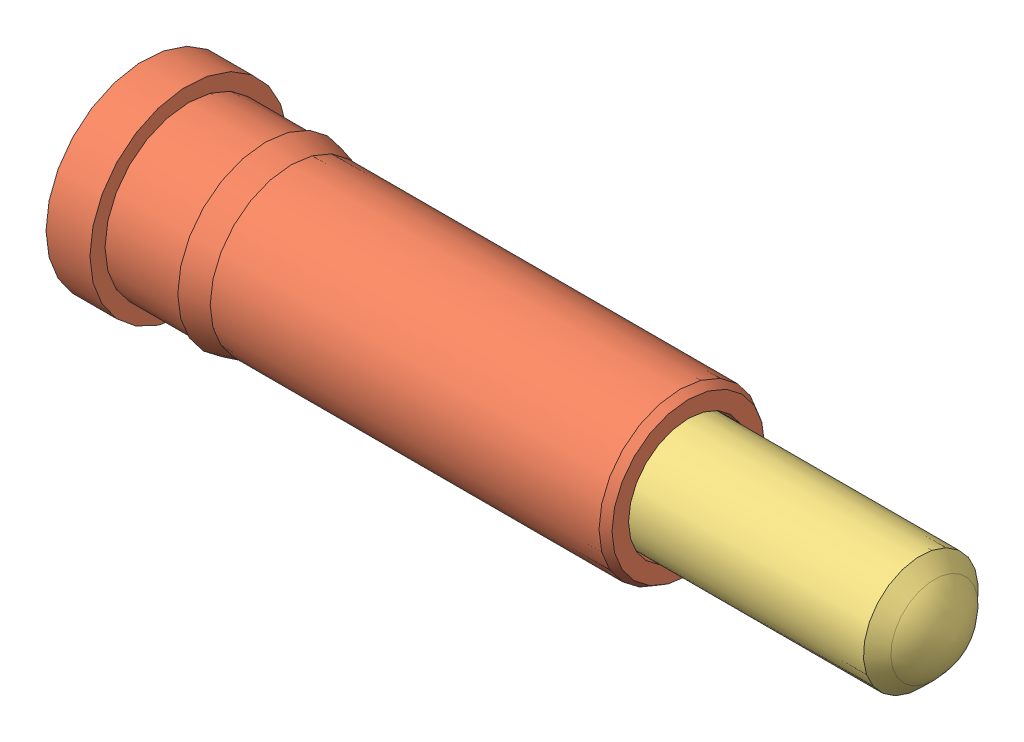
SolidWorks assembly mill-max-0928-0-15-20-77-14-11-0, configuration default. Lengths in mm.
Overall size (7.49 1.83 1.83).
4 component instances, 4 part files, 5 mates.
Components (placement in the parent):
- mill-max-0928-0-15-20-77-14-11-0_0960-X-1: mill-max-0928-0-15-20-77-14-11-0_0960-X [0960-0-00-20-00-00-13-0] at origin size (2.29 1.31 1.31)
- mill-max-0928-0-15-20-77-14-11-0_6958-0-1: mill-max-0928-0-15-20-77-14-11-0_6958-0 [6958-0-00-20-00-00-13-0] at origin size (5.03 1.83 1.83)
- mill-max-0928-0-15-20-77-14-11-0_6914-0-1: mill-max-0928-0-15-20-77-14-11-0_6914-0 [6914-0-00-20-00-00-13-0] at (2.794 0 0) x (1 0 0) z (0 0.193519 0.981096) size (4.7 1.25 1.25)
- mill-max-0928-0-15-20-77-14-11-0_SPRING-1: mill-max-0928-0-15-20-77-14-11-0_SPRING [0977-0-00-00-77-14-45-0] at (5.1889 0 0) x (0 -0.998361 0.057238) z (-1 0 0) size (0.86 0.99 4.9)
Mates (geometry in assembly coordinates):
- Concentric2: concentric aligned: circle of mill-max-0928-0-15-20-77-14-11-0_0960-X-1; circle of mill-max-0928-0-15-20-77-14-11-0_6958-0-1
- Coincident1: coincident aligned: plane of mill-max-0928-0-15-20-77-14-11-0_0960-X-1 through (0 0 0) normal (-1 0 0); plane of mill-max-0928-0-15-20-77-14-11-0_6958-0-1 through (0 0 0) normal (-1 0 0)
- Concentric3: concentric aligned: circle of mill-max-0928-0-15-20-77-14-11-0_6958-0-1; circle of mill-max-0928-0-15-20-77-14-11-0_6914-0-1
- Distance1: distance = 2.2352 mm anti-aligned: plane of mill-max-0928-0-15-20-77-14-11-0_6958-0-1 through (5.0292 0.7053 0) normal (1 0 0); plane of mill-max-0928-0-15-20-77-14-11-0_6914-0-1 through (2.794 0 0) normal (-1 0 0)
- Concentric4: concentric aligned: cylinder of mill-max-0928-0-15-20-77-14-11-0_0960-X-1 through (0 0 0) axis (-1 0 0) radius 0.2159; line of mill-max-0928-0-15-20-77-14-11-0_SPRING-1 through (5.1889 0 0) axis (-1 0 0)
